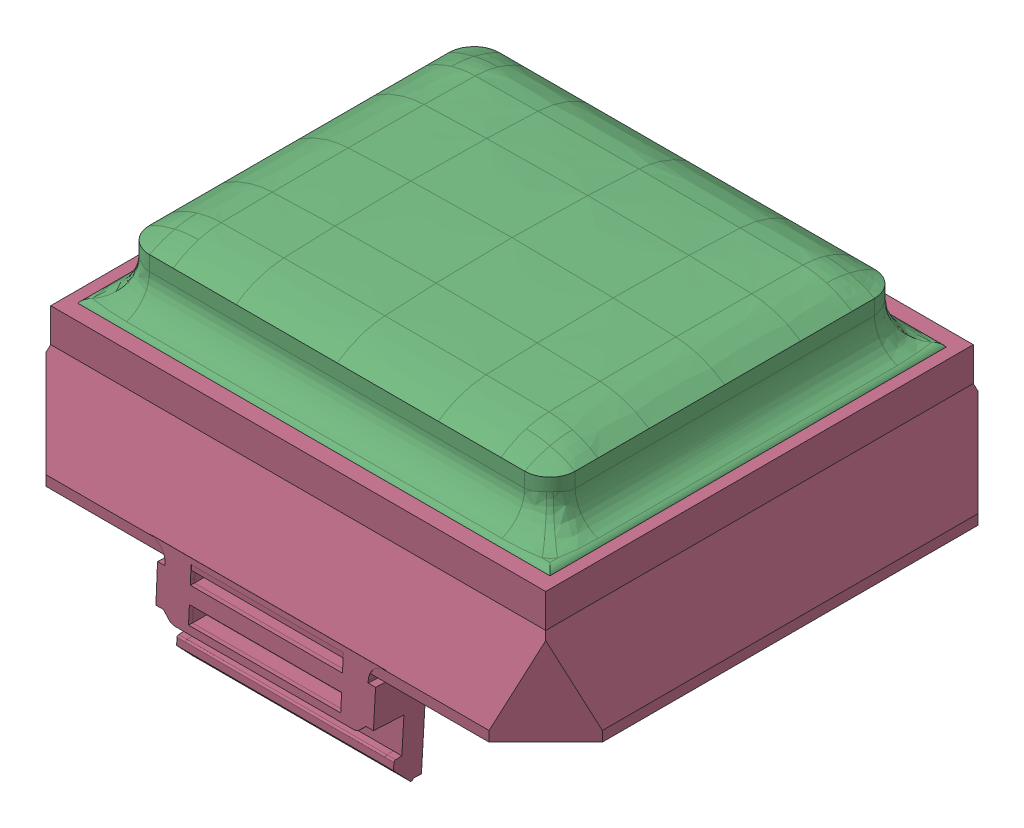
SolidWorks assembly Dot2V2, configuration 默认. Lengths in mm.
Overall size (33 18.27 29.5).
6 component instances, 5 part files, 23 mates.
Components (placement in the parent):
- Dot2V2Lens-1: Dot2V2Lens [默认] at origin size (28.33 2.18 23.83)
- Dot2V2InsideSkin-1: Dot2V2InsideSkin [默认] at (0.0001 0 0.2499) size (23.8 5.48 19.29)
- Dot2V2Topskin-1: Dot2V2Topskin [默认] at (0.0001 2 0.2499) size (28.02 6.25 23.52)
- Dot2V2Supportbase-2: Dot2V2Supportbase [默认] at origin size (33 14.02 29.5)
- Dot2V2Dor-1: Dot2V2Dor [默认] at (-1.2499 23.9 -0.9614) x (-1 0 0) z (0 -1 0) size (18.98 16.99 1.63)
- Dot2V2Dor-2: Dot2V2Dor [默认] at (-1.2499 22.7 -0.9614) x (-1 0 0) z (0 -1 0) size (18.98 16.99 1.63)
Mates (geometry in assembly coordinates):
- 同心2: concentric anti-aligned: cylinder of InsideSkin-1 through (10.8751 17.7531 8.6249) axis (0 1 0) radius 0.7; cylinder of Board3Con1612611OriginalSkin_TOP-1 through (10.8751 24 8.6249) axis (0 -1 0) radius 0.7
- 同心3: concentric anti-aligned: cylinder of InsideSkin-1 through (10.8751 17.7531 -9.1251) axis (0 1 0) radius 0.7; cylinder of Board3Con1612611OriginalSkin_TOP-1 through (10.8751 24 -9.1251) axis (0 -1 0) radius 0.7
- 重合4: coincident aligned: plane of InsideSkin-1 through (10.8751 19 -9.1251) normal (0 -1 0); plane of Board3Con1612611OriginalSkin_TOP-1 through (0.0001 19 0.2499) normal (0 -1 0)
- 重合6: coordinate: point of NewContiSupportBase-2
- 重合7: coincident anti-aligned: plane of lensall-1 through (13.75 19 -11.5) normal (0.939693 0.34202 0); plane of NewContiSupportBase-2 through (13.75 19 12.7803) normal (-0.939693 -0.34202 0)
- 同心5: concentric aligned: cylinder of lensall-1 through (13.3294 18.6938 -11.0794) axis (-0.323616 0.889126 0.323616) radius 0.5; cylinder of NewContiSupportBase-2 through (10.7866 25.6801 -8.5366) axis (-0.323616 0.889126 0.323616) radius 0.5
- 重合8: coincident anti-aligned: plane of lensall-1 through (0 18 0) normal (0 -1 0); plane of NewContiSupportBase-2 through (0 18 0) normal (0 1 0)
- 重合9: coincident anti-aligned: plane of lensall-1 through (0 19 0) normal (0 1 0); plane of Board3Con1612611OriginalSkin_TOP-1 through (0.0001 19 0.2499) normal (0 -1 0)
- 重合10: coincident anti-aligned: plane of Board3Con1612611OriginalSkin_TOP-1 through (0.0001 19 11.7499) normal (0 0 1); plane of NewContiSupportBase-2 through (-13.5999 21 11.7499) normal (0 0 -1)
- 重合11: coincident anti-aligned: plane of Board3Con1612611OriginalSkin_TOP-1 through (14.0001 19 0.2499) normal (1 0 0); plane of NewContiSupportBase-2 through (14.0001 21 11.7499) normal (-1 0 0)
- 平行1: parallel: plane of InsideSkin-1 through (-11.3749 17.7531 9.3249) normal (0 0 1); line of Dor-1 through (8.7251 23.9 6.9749) axis (-1 0 0)
- 平行2: parallel: plane of InsideSkin-1 through (-12.0749 17.7531 -9.1251) normal (-1 0 0); line of Dor-1 through (-12.2749 23.9 -8.0251) axis (0 0 1)
- 距离1: distance = 1.8 mm: line of Dor-1 through (8.7251 23.9 -8.0251) axis (-1 0 0); plane of InsideSkin-1 through (-11.3749 17.7531 -9.8251) normal (0 0 -1)
- 平行3: parallel anti-aligned: line of Supportbase-2 through (14.6801 19 12.1801) axis (0 0 -1); line of Dor-1 through (9.9597 23.9 -9.2955) axis (0 0 1)
- 距离2: distance = 5 mm: plane of Lens-1 through (0 19 0) normal (0 1 0); line of Dor-1 through (-12.2749 23.9 -8.0251) axis (0 0 1)
- 距离3: distance = 2.85 mm: plane of InsideSkin-1 through (11.5751 17.7531 -9.1251) normal (1 0 0); line of Dor-1 through (8.7251 23.9 -8.0251) axis (0 0 1)
- 平行4: parallel aligned: line of Supportbase-2 through (14.1801 19 -12.6801) axis (-1 0 0); line of Dor-1 through (9.9597 23.9 10.7045) axis (-1 0 0)
- 距离5: distance = 4.9 mm: plane of Lens-1 through (0 19 0) normal (0 1 0); line of Dor-1 through (8.7251 23.9 -8.0251) axis (0 0 1)
- 平行5: parallel aligned: line of Dor-1 through (-9.2581 23.9 7.9601) axis (1 0 0); line of Dor-2 through (-9.2581 22.7 7.9601) axis (1 0 0)
- 平行6: parallel aligned: line of Dor-1 through (-9.2581 23.9 -8.0251) axis (0 0 1); line of Dor-2 through (-9.2581 22.7 -8.0251) axis (0 0 1)
- 距离6: distance = 3.7 mm: plane of Lens-1 through (0 19 0) normal (0 1 0); line of Dor-2 through (8.7251 22.7 -8.0251) axis (0 0 1)
- 距离7: distance = 1.2 mm: line of Dor-2 through (-9.2581 22.7 -8.0251) axis (1 0 0); line of Dor-1 through (-9.2581 23.9 -8.0251) axis (1 0 0)
- 距离8: distance = 1.2 mm: line of Dor-2 through (8.7251 22.7 -8.0251) axis (0 0 1); line of Dor-1 through (8.7251 23.9 -8.0251) axis (0 0 1)
